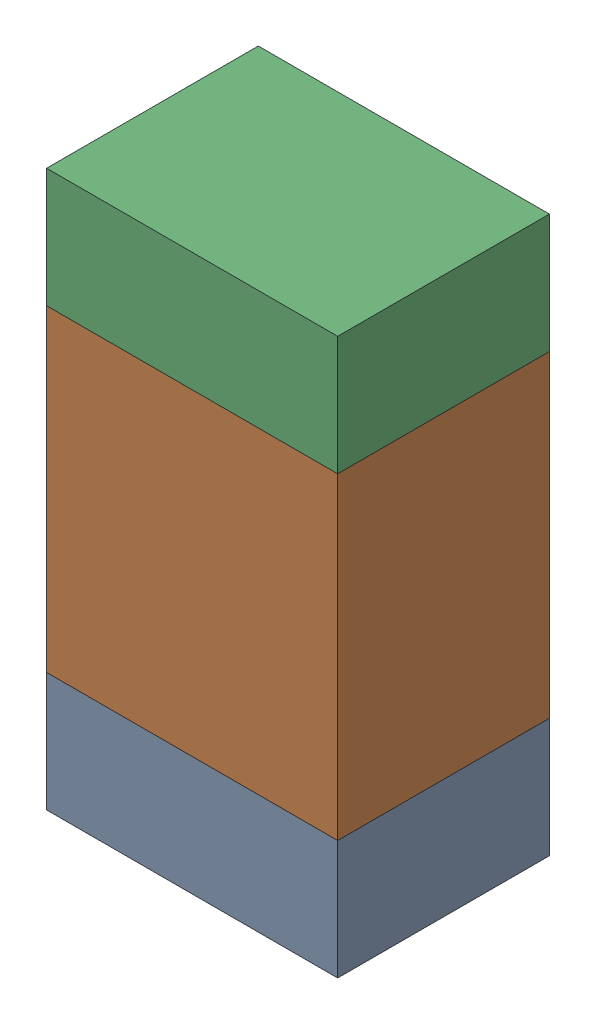
SolidWorks assembly R301_2PCB, configuration Default. Lengths in mm.
Overall size (0.55 1.05 0.4).
6 component instances, 2 part files, 0 mates.
Components (placement in the parent):
- 846483288-1: 846483288 [Default] at (154.3753 98.6055 0) size (0.55 0.22 0.4)
  - Extruded_12-1: Extruded_12 [Default] at origin size (0.55 0.22 0.4)
- 846483424-1: 846483424 [Default] at (154.3753 99.018 0) size (0.55 0.6 0.4)
  - Extruded_13-1: Extruded_13 [Default] at origin size (0.55 0.6 0.4)
- 846483288-2: 846483288 [Default] at (154.3753 99.4305 0) size (0.55 0.22 0.4)
  - Extruded_12-1: Extruded_12 [Default] at origin size (0.55 0.22 0.4)
